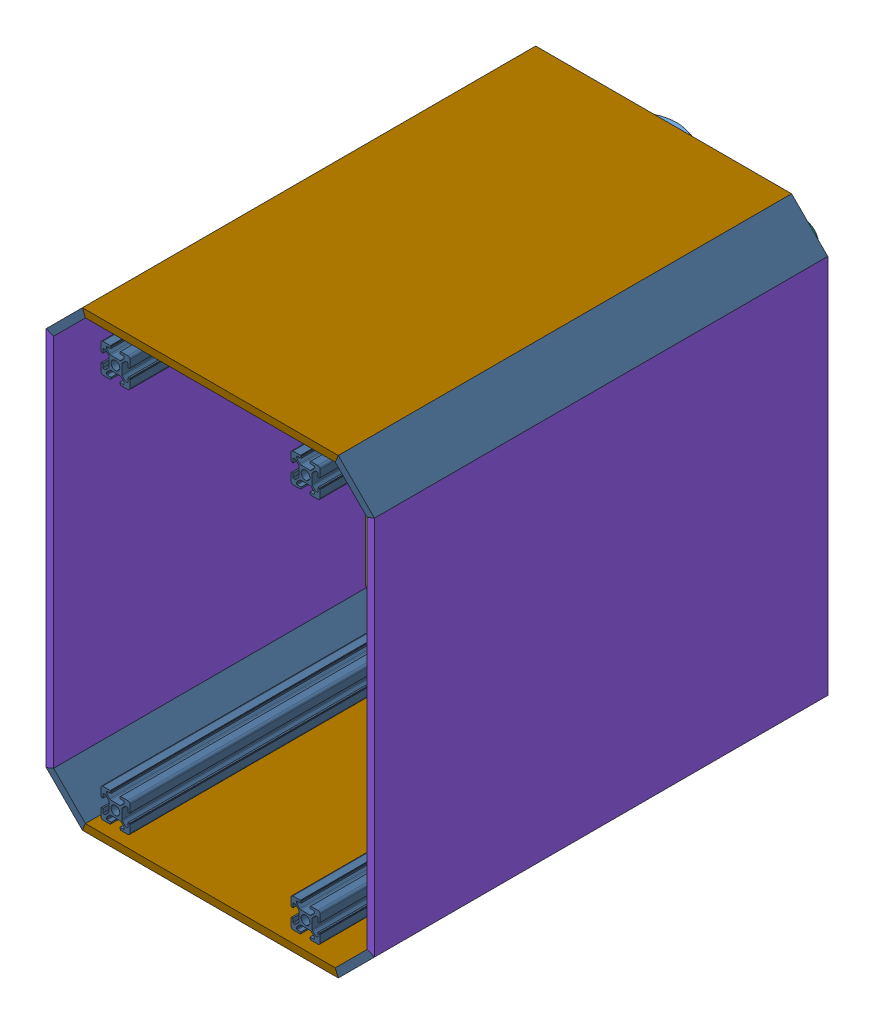
SolidWorks assembly base roulante, configuration Défaut. Lengths in mm.
Overall size (224.5 330.12 334.69).
128 component instances, 29 part files, 71 mates.
Components (placement in the parent):
- plaque base roulante 2-1: plaque base roulante 2 [Défaut] at (315.8571 -54.1365 122.0217) size (224.5 309.5 5)
- Assemblage 5mm-1: Assemblage 5mm [Défaut] at (210.2333 207.5126 153.7073) x (0.837948 0 -0.54575) z (0 -1 0) size (70.03 70.03 25.12)
  - moyeu pololu (axe 5mm) part 2-1: moyeu pololu (axe 5mm) part 2 [Défaut] at (16.3796 8.0597 10.6516) size (21.9 21.9 3)
  - moyeux pololu (axe 5mm)-1: moyeux pololu (axe 5mm) [Défaut] at (16.3796 8.0597 27.1516) x (0.866025 0.5 0) z (0 0 1) size (22 22 12)
  - Roue Scooter noire 70x25 mm 3272-1: Roue Scooter noire 70x25 mm 3272 [Défaut] at (16.3796 8.0597 22.1516) size (70.03 70.03 25.12)
- Assemblage 5mm-2: Assemblage 5mm [Défaut] at (224.692 -6.2881 169.4052) x (0.612655 0 -0.79035) z (0 1 0) size (70.03 70.03 25.12)
  - moyeu pololu (axe 5mm) part 2-1: moyeu pololu (axe 5mm) part 2 [Défaut] at (16.3796 8.0597 10.6516) size (21.9 21.9 3)
  - moyeux pololu (axe 5mm)-1: moyeux pololu (axe 5mm) [Défaut] at (16.3796 8.0597 27.1516) x (0.866025 0.5 0) z (0 0 1) size (22 22 12)
  - Roue Scooter noire 70x25 mm 3272-1: Roue Scooter noire 70x25 mm 3272 [Défaut] at (16.3796 8.0597 22.1516) size (70.03 70.03 25.12)
- Assemblage Roue Porteuse-1: Assemblage Roue Porteuse [Défaut] at (287.0912 226.3354 157.1111) x (0 -1 0) z (-1 0 0) size (40 50.71 20)
  - Support Bille porteuse-1: Support Bille porteuse [Défaut] at (1.9744 -30.0894 -26.9817) size (40 23 20)
  - Ecrou M6-3: Ecrou M6 [Défaut] at (1.9744 -17.1894 -26.9817) x (1 0 0) z (0 -1 0) size (12 12 5)
  - Ecrou M6-2: Ecrou M6 [Défaut] at (1.9744 -1.3894 -26.9817) x (1 0 0) z (0 -1 0) size (12 12 5)
  - Bille porteuse ALWAYE D12_7-2: Bille porteuse ALWAYE D12_7 [Défaut] at (1.9744 -30.1894 -26.9817) size (20 46.5 20)
  - Bille D12-2: Bille D12 [Défaut] at (1.9744 -38.8998 -26.9817) size (12 12 12)
  - Insert M4-2: Insert M4 [Défaut] at (16.9744 -30.0894 -26.9817) x (-0.837169 0 -0.546944) z (0 1 0) size (7 7 8)
  - Insert M4-3: Insert M4 [Défaut] at (-13.0256 -30.0894 -26.9817) x (-0.837169 0 -0.546944) z (0 1 0) size (7 7 8)
  - Rondelle M6-6: Rondelle M6 [Défaut] at (1.9744 -17.1894 -26.9817) x (1 0 0) z (0 1 0) size (14 14 0.7)
  - Rondelle M6-7: Rondelle M6 [Défaut] at (1.9744 -16.4894 -26.9817) x (1 0 0) z (0 1 0) size (14 14 0.7)
  - Rondelle M6-5: Rondelle M6 [Défaut] at (1.9744 -15.7894 -26.9817) x (1 0 0) z (0 1 0) size (14 14 0.7)
  - Rondelle M6-4: Rondelle M6 [Défaut] at (1.9744 -7.0894 -26.9817) x (1 0 0) z (0 1 0) size (14 14 0.7)
- Assemblage Roue Porteuse-2: Assemblage Roue Porteuse [Défaut] at (341.0545 -25.1109 157.1111) x (0 1 0) z (1 0 0) size (40 50.71 20)
  - Support Bille porteuse-1: Support Bille porteuse [Défaut] at (1.9744 -30.0894 -26.9817) size (40 23 20)
  - Ecrou M6-3: Ecrou M6 [Défaut] at (1.9744 -17.1894 -26.9817) x (1 0 0) z (0 -1 0) size (12 12 5)
  - Ecrou M6-2: Ecrou M6 [Défaut] at (1.9744 -1.3894 -26.9817) x (1 0 0) z (0 -1 0) size (12 12 5)
  - Bille porteuse ALWAYE D12_7-2: Bille porteuse ALWAYE D12_7 [Défaut] at (1.9744 -30.1894 -26.9817) size (20 46.5 20)
  - Bille D12-2: Bille D12 [Défaut] at (1.9744 -38.8998 -26.9817) size (12 12 12)
  - Insert M4-2: Insert M4 [Défaut] at (16.9744 -30.0894 -26.9817) x (-0.837169 0 -0.546944) z (0 1 0) size (7 7 8)
  - Insert M4-3: Insert M4 [Défaut] at (-13.0256 -30.0894 -26.9817) x (-0.837169 0 -0.546944) z (0 1 0) size (7 7 8)
  - Rondelle M6-6: Rondelle M6 [Défaut] at (1.9744 -17.1894 -26.9817) x (1 0 0) z (0 1 0) size (14 14 0.7)
  - Rondelle M6-7: Rondelle M6 [Défaut] at (1.9744 -16.4894 -26.9817) x (1 0 0) z (0 1 0) size (14 14 0.7)
  - Rondelle M6-5: Rondelle M6 [Défaut] at (1.9744 -15.7894 -26.9817) x (1 0 0) z (0 1 0) size (14 14 0.7)
  - Rondelle M6-4: Rondelle M6 [Défaut] at (1.9744 -7.0894 -26.9817) x (1 0 0) z (0 1 0) size (14 14 0.7)
- Assemblage Roue Porteuse-3: Assemblage Roue Porteuse [Défaut] at (169.6231 222.3866 157.1111) x (0 1 0) z (1 0 0) size (40 50.71 20)
  - Support Bille porteuse-1: Support Bille porteuse [Défaut] at (1.9744 -30.0894 -26.9817) size (40 23 20)
  - Ecrou M6-3: Ecrou M6 [Défaut] at (1.9744 -17.1894 -26.9817) x (1 0 0) z (0 -1 0) size (12 12 5)
  - Ecrou M6-2: Ecrou M6 [Défaut] at (1.9744 -1.3894 -26.9817) x (1 0 0) z (0 -1 0) size (12 12 5)
  - Bille porteuse ALWAYE D12_7-2: Bille porteuse ALWAYE D12_7 [Défaut] at (1.9744 -30.1894 -26.9817) size (20 46.5 20)
  - Bille D12-2: Bille D12 [Défaut] at (1.9744 -38.8998 -26.9817) size (12 12 12)
  - Insert M4-2: Insert M4 [Défaut] at (16.9744 -30.0894 -26.9817) x (-0.837169 0 -0.546944) z (0 1 0) size (7 7 8)
  - Insert M4-3: Insert M4 [Défaut] at (-13.0256 -30.0894 -26.9817) x (-0.837169 0 -0.546944) z (0 1 0) size (7 7 8)
  - Rondelle M6-6: Rondelle M6 [Défaut] at (1.9744 -17.1894 -26.9817) x (1 0 0) z (0 1 0) size (14 14 0.7)
  - Rondelle M6-7: Rondelle M6 [Défaut] at (1.9744 -16.4894 -26.9817) x (1 0 0) z (0 1 0) size (14 14 0.7)
  - Rondelle M6-5: Rondelle M6 [Défaut] at (1.9744 -15.7894 -26.9817) x (1 0 0) z (0 1 0) size (14 14 0.7)
  - Rondelle M6-4: Rondelle M6 [Défaut] at (1.9744 -7.0894 -26.9817) x (1 0 0) z (0 1 0) size (14 14 0.7)
- Assemblage Roue Porteuse-4: Assemblage Roue Porteuse [Défaut] at (169.6231 -25.1109 157.1111) x (0 1 0) z (1 0 0) size (40 50.71 20)
  - Support Bille porteuse-1: Support Bille porteuse [Défaut] at (1.9744 -30.0894 -26.9817) size (40 23 20)
  - Ecrou M6-3: Ecrou M6 [Défaut] at (1.9744 -17.1894 -26.9817) x (1 0 0) z (0 -1 0) size (12 12 5)
  - Ecrou M6-2: Ecrou M6 [Défaut] at (1.9744 -1.3894 -26.9817) x (1 0 0) z (0 -1 0) size (12 12 5)
  - Bille porteuse ALWAYE D12_7-2: Bille porteuse ALWAYE D12_7 [Défaut] at (1.9744 -30.1894 -26.9817) size (20 46.5 20)
  - Bille D12-2: Bille D12 [Défaut] at (1.9744 -38.8998 -26.9817) size (12 12 12)
  - Insert M4-2: Insert M4 [Défaut] at (16.9744 -30.0894 -26.9817) x (-0.837169 0 -0.546944) z (0 1 0) size (7 7 8)
  - Insert M4-3: Insert M4 [Défaut] at (-13.0256 -30.0894 -26.9817) x (-0.837169 0 -0.546944) z (0 1 0) size (7 7 8)
  - Rondelle M6-6: Rondelle M6 [Défaut] at (1.9744 -17.1894 -26.9817) x (1 0 0) z (0 1 0) size (14 14 0.7)
  - Rondelle M6-7: Rondelle M6 [Défaut] at (1.9744 -16.4894 -26.9817) x (1 0 0) z (0 1 0) size (14 14 0.7)
  - Rondelle M6-5: Rondelle M6 [Défaut] at (1.9744 -15.7894 -26.9817) x (1 0 0) z (0 1 0) size (14 14 0.7)
  - Rondelle M6-4: Rondelle M6 [Défaut] at (1.9744 -7.0894 -26.9817) x (1 0 0) z (0 1 0) size (14 14 0.7)
- Profilé Aluminium Bosch Rexroth 20 x 20 mm-1: Profilé Aluminium Bosch Rexroth 20 x 20 mm [Défaut] at (163.3571 232.361 127.0217) x (1 0 0) z (0 -1 0) size (20 310 20)
- Profilé Aluminium Bosch Rexroth 20 x 20 mm-2: Profilé Aluminium Bosch Rexroth 20 x 20 mm [Défaut] at (293.3571 -31.1365 127.0217) x (1 0 0) z (0 -1 0) size (20 310 20)
- Profilé Aluminium Bosch Rexroth 20 x 20 mm-3: Profilé Aluminium Bosch Rexroth 20 x 20 mm [Défaut] at (163.3571 -31.1365 127.0217) x (1 0 0) z (0 -1 0) size (20 310 20)
- Profilé Aluminium Bosch Rexroth 20 x 20 mm-4: Profilé Aluminium Bosch Rexroth 20 x 20 mm [Défaut] at (293.3571 232.361 127.0217) x (1 0 0) z (0 -1 0) size (20 310 20)
- Assemblage Systeme Encodeurs-1: Assemblage Systeme Encodeurs [Défaut] at (152.8693 -1.8671 137.3455) x (0.220763 0.975327 0) z (0.975327 -0.220763 0) size (62.28 94.74 89.05)
  - Axe_Support_Codeurs-1: Axe_Support_Codeurs [Défaut] at (-9.7273 -8.3238 48.8402) size (8 72 8)
  - Roulement linéaire-1: Roulement linéaire [Défaut] at (-9.7273 34.3589 48.8402) x (-0.971705 0 -0.236196) z (0 -1 0) size (15 15 24)
  - Support Ressort-1: Support Ressort [Défaut] at (-3.1044 51.6762 78.1001) x (0.220763 0 0.975327) z (-0.975327 0 0.220763) size (84.1 15.1 30.1)
  - Axe_Support_Codeurs-2: Axe_Support_Codeurs [Défaut] at (3.5185 -8.3238 107.3599) x (-0.166467 0 0.986047) z (-0.986047 0 -0.166467) size (8 72 8)
  - Roulement linéaire-2: Roulement linéaire [Défaut] at (3.5185 34.3589 107.3599) x (0.932325 0 -0.361623) z (0 -1 0) size (15 15 24)
  - Support Encodeurs-1: Support Encodeurs [Défaut] at (-3.1044 9.3589 78.1001) x (0.220763 0 0.975327) z (-0.975327 0 0.220763) size (84.1 37.8 24.1)
  - Rondelle M8-1: Rondelle M8 [Défaut] at (-9.7273 34.3589 48.8402) x (-0.837169 0 -0.546944) z (0 1 0) size (20 20 0.7)
  - Rondelle M8-2: Rondelle M8 [Défaut] at (3.5185 34.3589 107.3599) x (1 0 0) z (0 1 0) size (20 20 0.7)
  - Ressort M8-1: Ressort M8 [Défaut] at (3.5185 28.0864 107.3599) x (0.192743 0 -0.981249) z (0.981249 0 0.192743) size (12.72 24.18 12.45)
  - Ressort M8-2: Ressort M8 [Défaut] at (-9.7273 28.0864 48.8402) x (0.56484 0 0.8252) z (-0.8252 0 0.56484) size (12.72 24.18 12.45)
  - Insert M4-1: Insert M4 [Défaut] at (-21.1553 59.1762 52.7086) x (0.101832 0.887257 0.449894) z (0.975327 0 -0.220763) size (7 7 8)
  - Insert M4-4: Insert M4 [Défaut] at (-8.4614 59.1762 108.7899) x (0.099396 0.892908 0.439131) z (0.975327 0 -0.220763) size (7 7 8)
  - Codeurs Kuebler D24-2: Codeurs Kuebler D24 [Défaut] at (8.1118 8.8589 75.5613) x (-0.220763 0 -0.975327) z (-0.975327 0 0.220763) size (24 26 30.5)
  - Support Plaque Encodeurs-1: Support Plaque Encodeurs [Défaut] at (-3.1044 -10.3238 78.1001) x (0.220763 0 0.975327) z (-0.975327 0 0.220763) size (84 10 32)
  - Insert M4-5: Insert M4 [Défaut] at (6.1676 -4.8238 119.0638) x (-0.669085 -0.727591 0.151446) z (-0.220763 0 -0.975327) size (7 7 8)
  - Insert M4-6: Insert M4 [Défaut] at (-12.3765 -4.8238 37.1363) x (-0.897415 -0.391644 0.203128) z (0.220763 0 0.975327) size (7 7 8)
  - Insert M4-7: Insert M4 [Défaut] at (17.3015 -10.3238 109.3666) x (0.445123 0 0.895469) z (0 1 0) size (7 7 8)
  - Insert M4-8: Insert M4 [Défaut] at (1.8481 -10.3238 41.0937) x (0.956517 0 -0.291677) z (0 1 0) size (7 7 8)
  - Assemblage Roue Codeuse-1: Assemblage Roue Codeuse [Défaut] at (12.9164 -13.0885 115.5563) x (-0.212881 0.264817 -0.940507) z (0.975327 0 -0.220763) size (60 60 17)
    - Roue folle D56 BRS-1: Roue folle D56 BRS [Défaut] at (44.4504 10.553 -33.3566) size (56 56 17)
    - Joint Torique D52 T4 BRS-1: Joint Torique D52 T4 BRS [Défaut] at (44.4504 10.553 -29.8566) size (60 60 4)
- Assemblage Systeme Encodeurs-2: Assemblage Systeme Encodeurs [Défaut] at (303.8449 203.0915 137.3455) x (-0.220763 -0.975327 0) z (-0.975327 0.220763 0) size (62.28 94.74 89.05)
  - Axe_Support_Codeurs-1: Axe_Support_Codeurs [Défaut] at (-9.7273 -8.3238 48.8402) size (8 72 8)
  - Roulement linéaire-1: Roulement linéaire [Défaut] at (-9.7273 34.3589 48.8402) x (-0.971705 0 -0.236196) z (0 -1 0) size (15 15 24)
  - Support Ressort-1: Support Ressort [Défaut] at (-3.1044 51.6762 78.1001) x (0.220763 0 0.975327) z (-0.975327 0 0.220763) size (84.1 15.1 30.1)
  - Axe_Support_Codeurs-2: Axe_Support_Codeurs [Défaut] at (3.5185 -8.3238 107.3599) x (-0.166467 0 0.986047) z (-0.986047 0 -0.166467) size (8 72 8)
  - Roulement linéaire-2: Roulement linéaire [Défaut] at (3.5185 34.3589 107.3599) x (0.932325 0 -0.361623) z (0 -1 0) size (15 15 24)
  - Support Encodeurs-1: Support Encodeurs [Défaut] at (-3.1044 9.3589 78.1001) x (0.220763 0 0.975327) z (-0.975327 0 0.220763) size (84.1 37.8 24.1)
  - Rondelle M8-1: Rondelle M8 [Défaut] at (-9.7273 34.3589 48.8402) x (-0.837169 0 -0.546944) z (0 1 0) size (20 20 0.7)
  - Rondelle M8-2: Rondelle M8 [Défaut] at (3.5185 34.3589 107.3599) x (1 0 0) z (0 1 0) size (20 20 0.7)
  - Ressort M8-1: Ressort M8 [Défaut] at (3.5185 28.0864 107.3599) x (0.192743 0 -0.981249) z (0.981249 0 0.192743) size (12.72 24.18 12.45)
  - Ressort M8-2: Ressort M8 [Défaut] at (-9.7273 28.0864 48.8402) x (0.56484 0 0.8252) z (-0.8252 0 0.56484) size (12.72 24.18 12.45)
  - Insert M4-1: Insert M4 [Défaut] at (-21.1553 59.1762 52.7086) x (0.101832 0.887257 0.449894) z (0.975327 0 -0.220763) size (7 7 8)
  - Insert M4-4: Insert M4 [Défaut] at (-8.4614 59.1762 108.7899) x (0.099396 0.892908 0.439131) z (0.975327 0 -0.220763) size (7 7 8)
  - Codeurs Kuebler D24-2: Codeurs Kuebler D24 [Défaut] at (8.1118 8.8589 75.5613) x (-0.220763 0 -0.975327) z (-0.975327 0 0.220763) size (24 26 30.5)
  - Support Plaque Encodeurs-1: Support Plaque Encodeurs [Défaut] at (-3.1044 -10.3238 78.1001) x (0.220763 0 0.975327) z (-0.975327 0 0.220763) size (84 10 32)
  - Insert M4-5: Insert M4 [Défaut] at (6.1676 -4.8238 119.0638) x (-0.669085 -0.727591 0.151446) z (-0.220763 0 -0.975327) size (7 7 8)
  - Insert M4-6: Insert M4 [Défaut] at (-12.3765 -4.8238 37.1363) x (-0.897415 -0.391644 0.203128) z (0.220763 0 0.975327) size (7 7 8)
  - Insert M4-7: Insert M4 [Défaut] at (17.3015 -10.3238 109.3666) x (0.445123 0 0.895469) z (0 1 0) size (7 7 8)
  - Insert M4-8: Insert M4 [Défaut] at (1.8481 -10.3238 41.0937) x (0.956517 0 -0.291677) z (0 1 0) size (7 7 8)
  - Assemblage Roue Codeuse-1: Assemblage Roue Codeuse [Défaut] at (12.9164 -13.0885 115.5563) x (-0.212881 0.264817 -0.940507) z (0.975327 0 -0.220763) size (60 60 17)
    - Roue folle D56 BRS-1: Roue folle D56 BRS [Défaut] at (44.4504 10.553 -33.3566) size (56 56 17)
    - Joint Torique D52 T4 BRS-1: Joint Torique D52 T4 BRS [Défaut] at (44.4504 10.553 -29.8566) size (60 60 4)
- Assemblage Total moteur-cache-1: Assemblage Total moteur-cache [Défaut] at (226.6189 146.4147 155.6743) x (-1 0 0) z (0 -1 0) size (83 52 94.8)
  - Assemblage Moteur-réducteur Faulhaber-1: Assemblage Moteur-réducteur Faulhaber [Défaut] at (2.5405 0.6017 16.3513) size (42 48.5 94.7)
    - 4221G_BXTH _ moteur-1: 4221G_BXTH _ moteur [Défaut] at (-4.2788 3.5509 53) size (42 48.5 35)
    - 42gpt-2stage_standard+KSx _ reducteur-1: 42gpt-2stage_standard+KSx _ reducteur [Défaut] at (-138.2788 3.5509 53) size (42 42.04 72.7)
  - Cache moteur-1: Cache moteur [Défaut] at (-1.7383 4.1526 112.5513) x (1 0 0) z (0 0 -1) size (83 49 68.3)
- Assemblage Total moteur-cache-2: Assemblage Total moteur-cache [Défaut] at (230.0954 54.8097 155.6743) x (1 0 0) z (0 1 0) size (83 52 94.8)
  - Assemblage Moteur-réducteur Faulhaber-1: Assemblage Moteur-réducteur Faulhaber [Défaut] at (2.5405 0.6017 16.3513) size (42 48.5 94.7)
    - 4221G_BXTH _ moteur-1: 4221G_BXTH _ moteur [Défaut] at (-4.2788 3.5509 53) size (42 48.5 35)
    - 42gpt-2stage_standard+KSx _ reducteur-1: 42gpt-2stage_standard+KSx _ reducteur [Défaut] at (-138.2788 3.5509 53) size (42 42.04 72.7)
  - Cache moteur-1: Cache moteur [Défaut] at (-1.7383 4.1526 112.5513) x (1 0 0) z (0 0 -1) size (83 49 68.3)
- equerre profilé-1: equerre profilé [Défaut] at (293.3571 222.361 203.5788) x (0 0 -1) z (0 -1 0) size (30 20 32)
- equerre profilé-2: equerre profilé [Défaut] at (163.3571 -21.1365 203.5788) x (0 0 -1) z (0 1 0) size (30 20 32)
- equerre profilé-3: equerre profilé [Défaut] at (163.3571 222.361 203.5788) x (0 0 -1) z (0 -1 0) size (30 20 32)
- equerre profilé-4: equerre profilé [Défaut] at (293.3571 -21.1365 203.5788) x (0 0 -1) z (0 1 0) size (30 20 32)
- Plaque etage 2_plexi pris en compte-1: Plaque etage 2_plexi pris en compte [Défaut] at (228.3571 100.6122 218.5788) size (214.5 299.5 5)
- plexi_avant-1: plexi_avant [Défaut] at (121.1084 228.5422 127.0889) x (0 -1 0) z (-1 0 0) size (260 310 5)
- plexi_avant-2: plexi_avant [Défaut] at (335.6059 -27.3178 127.0889) x (0 1 0) z (1 0 0) size (260 310 5)
- plexi_coté-1: plexi_coté [Défaut] at (142.9271 -49.1365 127.0889) x (1 0 0) z (0 0 -1) size (175 5 310)
- plexi_coté-2: plexi_coté [Défaut] at (142.9271 250.361 437.0889) size (175 5 310)
- plexi_coin-1: plexi_coin [Défaut] at (142.9396 250.3723 437.0889) x (-0.707107 -0.707107 0) z (0.707107 -0.707107 0) size (35 310 5)
- plexi_coin-2: plexi_coin [Défaut] at (142.9396 -49.1479 127.0889) x (-0.707107 0.707107 0) z (0.707107 0.707107 0) size (35 310 5)
- plexi_coin-3: plexi_coin [Défaut] at (313.7747 -49.1479 437.0889) x (0.707107 0.707107 0) z (-0.707107 0.707107 0) size (35 310 5)
- plexi_coin-4: plexi_coin [Défaut] at (335.6172 228.5298 437.0889) x (-0.707107 0.707107 0) z (-0.707107 -0.707107 0) size (35 310 5)
Mates (geometry in assembly coordinates):
- Coïncidente7: coincident anti-aligned: plane of plaque base roulante 2-1 through (315.8571 -54.1365 127.0217) normal (0 0 1); plane of Assemblage Roue Porteuse-1/Support Bille porteuse-1 through (314.0729 224.361 127.0217) normal (0 0 -1)
- Coaxiale6: concentric anti-aligned: cylinder of plaque base roulante 2-1 through (314.0729 224.361 122.0207) axis (0 0 1) radius 11; cylinder of Assemblage Roue Porteuse-1/Bille porteuse ALWAYE D12_7-2 through (314.0729 224.361 130.9217) axis (0 0 -1) radius 10
- Coaxiale7: concentric anti-aligned: circle of plaque base roulante 2-1; cylinder of Assemblage Roue Porteuse-1/Insert M4-2 through (314.0729 209.361 135.0217) axis (0 0 -1) radius 2
- Coaxiale8: concentric anti-aligned: cylinder of plaque base roulante 2-1 through (314.0729 -23.1365 122.0207) axis (0 0 1) radius 11; cylinder of Assemblage Roue Porteuse-2/Bille porteuse ALWAYE D12_7-2 through (314.0729 -23.1365 130.9217) axis (0 0 -1) radius 10
- Coïncidente9: coincident anti-aligned: plane of plaque base roulante 2-1 through (315.8571 -54.1365 127.0217) normal (0 0 1); plane of Assemblage Roue Porteuse-2/Support Bille porteuse-1 through (314.0729 -23.1365 127.0217) normal (0 0 -1)
- Coaxiale9: concentric anti-aligned: cylinder of plaque base roulante 2-1 through (314.0729 -8.1365 122.0207) axis (0 0 1) radius 2; cylinder of Assemblage Roue Porteuse-2/Insert M4-2 through (314.0729 -8.1365 135.0217) axis (0 0 -1) radius 2
- Coïncidente10: coincident anti-aligned: plane of plaque base roulante 2-1 through (315.8571 -54.1365 127.0217) normal (0 0 1); plane of Assemblage Roue Porteuse-4/Support Bille porteuse-1 through (142.6414 -23.1365 127.0217) normal (0 0 -1)
- Coïncidente13: coincident anti-aligned: plane of plaque base roulante 2-1 through (315.8571 -54.1365 127.0217) normal (0 0 1); plane of Profilé Aluminium Bosch Rexroth 20 x 20 mm-3 through (163.3571 -31.1365 127.0217) normal (0 0 -1)
- Coïncidente14: coincident anti-aligned: plane of plaque base roulante 2-1 through (315.8571 -54.1365 127.0217) normal (0 0 1); plane of Profilé Aluminium Bosch Rexroth 20 x 20 mm-2 through (293.3571 -31.1365 127.0217) normal (0 0 -1)
- Coïncidente15: coincident anti-aligned: plane of plaque base roulante 2-1 through (315.8571 -54.1365 127.0217) normal (0 0 1); plane of Profilé Aluminium Bosch Rexroth 20 x 20 mm-4 through (293.3571 232.361 127.0217) normal (0 0 -1)
- Coïncidente16: coincident anti-aligned: plane of plaque base roulante 2-1 through (315.8571 -54.1365 127.0217) normal (0 0 1); plane of Profilé Aluminium Bosch Rexroth 20 x 20 mm-1 through (163.3571 232.361 127.0217) normal (0 0 -1)
- Coaxiale14: concentric anti-aligned: cylinder of plaque base roulante 2-1 through (163.3571 -31.1365 122.0207) axis (0 0 1) radius 3; cylinder of Profilé Aluminium Bosch Rexroth 20 x 20 mm-3 through (163.3571 -31.1365 437.0217) axis (0 0 -1) radius 3
- Coaxiale15: concentric anti-aligned: cylinder of plaque base roulante 2-1 through (293.3571 -31.1365 122.0207) axis (0 0 1) radius 3; cylinder of Profilé Aluminium Bosch Rexroth 20 x 20 mm-2 through (293.3571 -31.1365 437.0217) axis (0 0 -1) radius 3
- Coïncidente17: coincident anti-aligned: cylinder of plaque base roulante 2-1 through (293.3571 232.361 122.0207) axis (0 0 1) radius 3; circle of Profilé Aluminium Bosch Rexroth 20 x 20 mm-4
- Coïncidente18: coincident anti-aligned: circle of plaque base roulante 2-1; cylinder of Profilé Aluminium Bosch Rexroth 20 x 20 mm-1 through (163.3571 232.361 437.0217) axis (0 0 -1) radius 3
- Parallèle2: parallel aligned: plane of plaque base roulante 2-1 through (140.8571 255.361 127.0217) normal (0 1 0); plane of Profilé Aluminium Bosch Rexroth 20 x 20 mm-1 through (153.3571 242.361 437.0217) normal (0 1 0)
- Parallèle3: parallel aligned: plane of plaque base roulante 2-1 through (140.8571 255.361 127.0217) normal (0 1 0); plane of Profilé Aluminium Bosch Rexroth 20 x 20 mm-4 through (283.3571 242.361 437.0217) normal (0 1 0)
- Parallèle4: parallel aligned: plane of plaque base roulante 2-1 through (315.8571 -54.1365 127.0217) normal (0 -1 0); plane of Profilé Aluminium Bosch Rexroth 20 x 20 mm-3 through (173.3571 -41.1365 437.0217) normal (0 -1 0)
- Parallèle5: parallel: line of plaque base roulante 2-1 through (273.3571 -54.1365 122.0217) axis (1 0 0); plane of Profilé Aluminium Bosch Rexroth 20 x 20 mm-2 through (283.3571 -41.1365 437.0217) normal (0 -1 0)
- Coaxiale16: concentric anti-aligned: cylinder of plaque base roulante 2-1 through (142.6414 -23.1365 122.0207) axis (0 0 1) radius 11; cylinder of Assemblage Roue Porteuse-4/Bille porteuse ALWAYE D12_7-2 through (142.6414 -23.1365 130.9217) axis (0 0 -1) radius 10
- Coïncidente19: coincident aligned: cylinder of plaque base roulante 2-1 through (142.6414 -38.1365 122.0207) axis (0 0 1) radius 2; circle of Assemblage Roue Porteuse-4/Insert M4-3
- Coïncidente20: coincident anti-aligned: circle of plaque base roulante 2-1; circle of Assemblage Systeme Encodeurs-1/Insert M4-8
- Coaxiale19: concentric aligned: circle of plaque base roulante 2-1; circle of Assemblage Systeme Encodeurs-1/Insert M4-7
- Coïncidente21: coincident anti-aligned: circle of plaque base roulante 2-1; circle of Assemblage Systeme Encodeurs-2/Insert M4-8
- Coïncidente22: coincident anti-aligned: circle of plaque base roulante 2-1; circle of Assemblage Systeme Encodeurs-2/Insert M4-7
- Coïncidente24: coincident aligned: circle of plaque base roulante 2-1; circle of Assemblage Total moteur-cache-1/Cache moteur-1
- Coïncidente25: coincident aligned: circle of plaque base roulante 2-1; circle of Assemblage Total moteur-cache-1/Cache moteur-1
- Coïncidente26: coincident aligned: circle of plaque base roulante 2-1; circle of Assemblage Total moteur-cache-2/Cache moteur-1
- Coïncidente27: coincident aligned: circle of plaque base roulante 2-1; circle of Assemblage Total moteur-cache-2/Cache moteur-1
- Coïncidente29: coincident aligned: plane of Assemblage 5mm-2/moyeu pololu (axe 5mm) part 2-1 through (228.3571 4.3635 151.5217) normal (0 -1 0); plane of Assemblage Total moteur-cache-1/Assemblage Moteur-réducteur Faulhaber-1/42gpt-2stage_standard+KSx _ reducteur-1 through (228.3571 4.3635 151.5217) normal (0 -1 0)
- Coaxiale20: concentric anti-aligned: circle of Assemblage 5mm-2/moyeu pololu (axe 5mm) part 2-1; circle of Assemblage Total moteur-cache-1/Assemblage Moteur-réducteur Faulhaber-1/42gpt-2stage_standard+KSx _ reducteur-1
- Coïncidente30: coincident aligned: plane of Assemblage 5mm-1/moyeu pololu (axe 5mm) part 2-1 through (228.3571 196.861 151.5217) normal (0 1 0); plane of Assemblage Total moteur-cache-2/Assemblage Moteur-réducteur Faulhaber-1/42gpt-2stage_standard+KSx _ reducteur-1 through (228.3571 196.861 151.5217) normal (0 1 0)
- Coaxiale21: concentric anti-aligned: circle of Assemblage 5mm-1/moyeu pololu (axe 5mm) part 2-1; circle of Assemblage Total moteur-cache-2/Assemblage Moteur-réducteur Faulhaber-1/42gpt-2stage_standard+KSx _ reducteur-1
- Coïncidente33: coincident aligned: circle of plaque base roulante 2-1; circle of Assemblage Roue Porteuse-3/Insert M4-2
- Coaxiale23: concentric aligned: circle of plaque base roulante 2-1; circle of Assemblage Roue Porteuse-3/Insert M4-3
- Coïncidente34: coincident anti-aligned: plane of Profilé Aluminium Bosch Rexroth 20 x 20 mm-4 through (303.3571 222.361 437.0217) normal (0 -1 0); plane of equerre profilé-1 through (293.3571 222.361 203.5788) normal (0 1 0)
- Coïncidente35: coincident aligned: plane of Profilé Aluminium Bosch Rexroth 20 x 20 mm-4 through (303.3571 228.861 437.0217) normal (1 0 0); plane of equerre profilé-1 through (303.3571 220.361 218.5788) normal (1 0 0)
- Coïncidente36: coincident anti-aligned: plane of Profilé Aluminium Bosch Rexroth 20 x 20 mm-1 through (173.3571 222.361 437.0217) normal (0 -1 0); plane of equerre profilé-3 through (163.3571 222.361 203.5788) normal (0 1 0)
- Coïncidente37: coincident aligned: plane of Profilé Aluminium Bosch Rexroth 20 x 20 mm-1 through (173.3571 228.861 437.0217) normal (1 0 0); plane of equerre profilé-3 through (173.3571 220.361 218.5788) normal (1 0 0)
- Coïncidente38: coincident anti-aligned: plane of Profilé Aluminium Bosch Rexroth 20 x 20 mm-3 through (153.3571 -21.1365 437.0217) normal (0 1 0); plane of equerre profilé-2 through (163.3571 -21.1365 203.5788) normal (0 -1 0)
- Coïncidente39: coincident aligned: plane of Profilé Aluminium Bosch Rexroth 20 x 20 mm-3 through (173.3571 -27.6365 437.0217) normal (1 0 0); plane of equerre profilé-2 through (173.3571 -19.1365 218.5788) normal (1 0 0)
- Coïncidente40: coincident anti-aligned: plane of Profilé Aluminium Bosch Rexroth 20 x 20 mm-2 through (283.3571 -21.1365 437.0217) normal (0 1 0); plane of equerre profilé-4 through (293.3571 -21.1365 203.5788) normal (0 -1 0)
- Coïncidente41: coincident aligned: plane of Profilé Aluminium Bosch Rexroth 20 x 20 mm-2 through (303.3571 -27.6365 437.0217) normal (1 0 0); plane of equerre profilé-4 through (303.3571 -19.1365 218.5788) normal (1 0 0)
- Coïncidente42: coincident aligned: plane of equerre profilé-2 through (173.3571 -19.1365 218.5788) normal (0 0 1); plane of equerre profilé-3 through (153.3571 220.361 218.5788) normal (0 0 1)
- Coïncidente43: coincident aligned: plane of equerre profilé-2 through (173.3571 -19.1365 218.5788) normal (0 0 1); plane of equerre profilé-4 through (303.3571 -19.1365 218.5788) normal (0 0 1)
- Coïncidente44: coincident aligned: plane of equerre profilé-1 through (283.3571 220.361 218.5788) normal (0 0 1); plane of equerre profilé-2 through (173.3571 -19.1365 218.5788) normal (0 0 1)
- Coïncidente45: coincident anti-aligned: plane of Profilé Aluminium Bosch Rexroth 20 x 20 mm-4 through (303.3571 235.861 437.0217) normal (1 0 0); plane of Plaque etage 2_plexi pris en compte-1 through (303.3571 242.361 218.5788) normal (-1 0 0)
- Coïncidente46: coincident anti-aligned: plane of Profilé Aluminium Bosch Rexroth 20 x 20 mm-4 through (283.3571 242.361 437.0217) normal (0 1 0); plane of Plaque etage 2_plexi pris en compte-1 through (303.3571 242.361 218.5788) normal (0 -1 0)
- Coïncidente47: coincident anti-aligned: plane of equerre profilé-3 through (153.3571 220.361 218.5788) normal (0 0 1); plane of Plaque etage 2_plexi pris en compte-1 through (228.3571 100.6122 218.5788) normal (0 0 -1)
- Coïncidente61: coincident aligned: plane of plexi_avant-2 through (340.6059 -27.3178 437.0889) normal (0 0 1); plane of plexi_coté-2 through (142.9271 255.361 437.0889) normal (0 0 1)
- Coïncidente65: coincident aligned: plane of plaque base roulante 2-1 through (340.6059 230.6122 127.0217) normal (1 0 0); plane of plexi_avant-2 through (340.6059 -27.3178 127.0889) normal (1 0 0)
- Coïncidente66: coincident aligned: plane of plaque base roulante 2-1 through (140.8571 255.361 127.0217) normal (0 1 0); plane of plexi_coté-2 through (142.9271 255.361 437.0889) normal (0 1 0)
- Coïncidente69: coincident aligned: plane of plexi_avant-2 through (340.6059 -27.3178 437.0889) normal (0 0 1); plane of plexi_coin-1 through (142.9396 250.3723 437.0889) normal (0 0 1)
- Coïncidente73: coincident aligned: plane of plaque base roulante 2-1 through (116.1084 230.6122 127.0217) normal (-0.707107 0.707107 0); plane of plexi_coin-1 through (140.8571 255.361 127.0889) normal (-0.707107 0.707107 0)
- Coïncidente74: coincident aligned: plane of plexi_avant-1 through (116.1084 228.5422 437.0889) normal (0 0 1); plane of plexi_coté-2 through (142.9271 255.361 437.0889) normal (0 0 1)
- Coïncidente75: coincident aligned: plane of plaque base roulante 2-1 through (116.1084 -29.3878 127.0217) normal (-1 0 0); plane of plexi_avant-1 through (116.1084 228.5422 127.0889) normal (-1 0 0)
- Coïncidente79: coincident aligned: line of plexi_avant-1 through (116.1084 230.6122 127.0889) axis (0 0 1); line of plexi_coin-1 through (116.1084 230.6122 127.0889) axis (0 0 1)
- Coïncidente80: coincident anti-aligned: line of plexi_coté-2 through (140.8571 255.361 437.0889) axis (0 0 -1); line of plexi_coin-1 through (140.8571 255.361 127.0889) axis (0 0 1)
- Coïncidente81: coincident aligned: plane of plexi_avant-2 through (340.6059 -27.3178 437.0889) normal (0 0 1); plane of plexi_coté-1 through (142.9271 -54.1365 437.0889) normal (0 0 1)
- Coïncidente82: coincident aligned: plane of plaque base roulante 2-1 through (315.8571 -54.1365 127.0217) normal (0 -1 0); plane of plexi_coté-1 through (142.9271 -54.1365 127.0889) normal (0 -1 0)
- Coïncidente83: coincident aligned: plane of plaque base roulante 2-1 through (140.8571 -54.1365 127.0217) normal (-0.707107 -0.707107 0); plane of plexi_coin-2 through (140.8571 -54.1365 437.0889) normal (-0.707107 -0.707107 0)
- Coïncidente84: coincident aligned: plane of plexi_avant-1 through (116.1084 228.5422 437.0889) normal (0 0 1); plane of plexi_coin-2 through (142.9396 -49.1479 437.0889) normal (0 0 1)
- Coïncidente85: coincident anti-aligned: line of plexi_avant-1 through (116.1084 -29.3878 127.0889) axis (0 0 1); line of plexi_coin-2 through (116.1084 -29.3878 437.0889) axis (0 0 -1)
- Coïncidente86: coincident anti-aligned: line of plexi_coté-1 through (140.8571 -54.1365 127.0889) axis (0 0 1); line of plexi_coin-2 through (140.8571 -54.1365 437.0889) axis (0 0 -1)
- Coïncidente87: coincident aligned: plane of plexi_coté-1 through (142.9271 -54.1365 437.0889) normal (0 0 1); plane of plexi_coin-3 through (313.7747 -49.1479 437.0889) normal (0 0 1)
- Coïncidente88: coincident aligned: plane of plaque base roulante 2-1 through (340.6059 -29.3878 127.0217) normal (0.707107 -0.707107 0); plane of plexi_coin-3 through (315.8571 -54.1365 127.0889) normal (0.707107 -0.707107 0)
- Coïncidente89: coincident aligned: line of plexi_coté-1 through (315.8571 -54.1365 127.0889) axis (0 0 1); line of plexi_coin-3 through (315.8571 -54.1365 127.0889) axis (0 0 1)
- Coïncidente90: coincident aligned: line of plexi_avant-2 through (340.6059 -29.3878 127.0889) axis (0 0 1); line of plexi_coin-3 through (340.6059 -29.3878 127.0889) axis (0 0 1)
- Coïncidente91: coincident aligned: plane of plexi_avant-2 through (340.6059 -27.3178 437.0889) normal (0 0 1); plane of plexi_coin-4 through (335.6172 228.5298 437.0889) normal (0 0 1)
- Coïncidente92: coincident aligned: plane of plaque base roulante 2-1 through (315.8571 255.361 127.0217) normal (0.707107 0.707107 0); plane of plexi_coin-4 through (340.6059 230.6122 127.0889) normal (0.707107 0.707107 0)
- Coïncidente93: coincident aligned: line of plexi_avant-2 through (340.6059 230.6122 127.0889) axis (0 0 1); line of plexi_coin-4 through (340.6059 230.6122 127.0889) axis (0 0 1)
